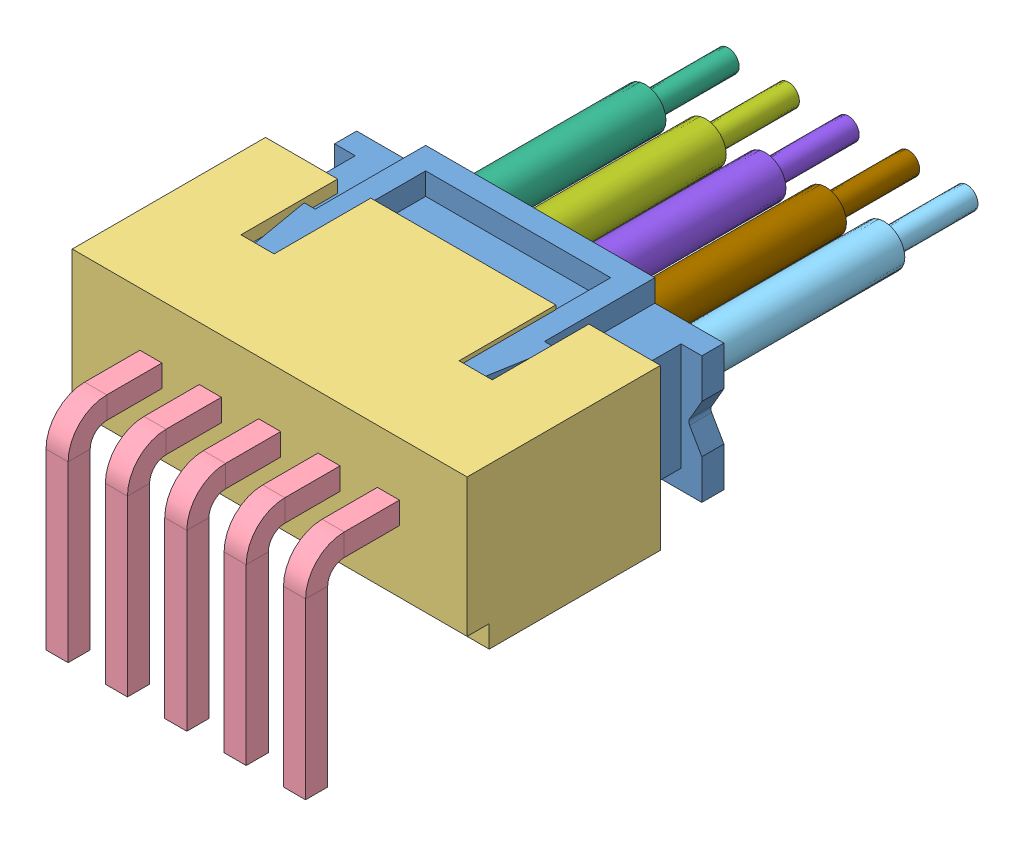
SolidWorks assembly Assem2, configuration Default. Lengths in mm.
Overall size (14.3 9.85 24.36).
17 component instances, 9 part files, 33 mates.
Components (placement in the parent):
- JST - XH MALE 5 pin-1: JST - XH MALE 5 pin [Default] at (8.2428 8.3107 7.5483) size (13.3 5.4 8.4)
- Part1-2: Part1 [Default] at (12.5428 8.6607 13.8683) x (1 0 0) z (0 1 0) size (1.8 6 3.23)
- Part1-3: Part1 [Default] at (10.3928 8.6607 13.8683) x (1 0 0) z (0 1 0) size (1.8 6 3.23)
- Part1-4: Part1 [Default] at (6.0928 8.6607 13.8683) x (1 0 0) z (0 1 0) size (1.8 6 3.23)
- Part1-5: Part1 [Default] at (8.2428 8.6607 13.8683) x (1 0 0) z (0 1 0) size (1.8 6 3.23)
- Part1-6: Part1 [Default] at (3.9428 8.6607 13.8683) x (1 0 0) z (0 1 0) size (1.8 6 3.23)
- Part 2-1: Part 2 [Default] at (8.2428 8.5107 9.5483) x (-1 0 0) z (0 1 0) size (14.3 7 5.8)
- Part3-1: Part3 [Default] at (10.3928 9.0607 19.5483) x (0 0 1) z (-1 0 0) size (9.7 7.9 0.8)
- Part3-2: Part3 [Default] at (12.5428 9.0607 19.5483) x (0 0 1) z (-1 0 0) size (9.7 7.9 0.8)
- Part3-3: Part3 [Default] at (8.2428 9.0607 19.5483) x (0 0 1) z (-1 0 0) size (9.7 7.9 0.8)
- Part3-4: Part3 [Default] at (3.9428 9.0607 19.5483) x (0 0 1) z (-1 0 0) size (9.7 7.9 0.8)
- Part3-6: Part3 [Default] at (6.0928 9.0607 19.5483) x (0 0 1) z (-1 0 0) size (9.7 7.9 0.8)
- Part4-1: Part4 [Default] at (12.5672 8.3011 -1.3782) size (1.5 1.5 16)
- Part5-1: Part5 [Default] at (3.9383 8.295 -1.3574) size (1.5 1.5 16)
- Part6-1: Part6 [Default] at (6.0987 8.2852 -1.381) size (1.5 1.5 16)
- Part7-1: Part7 [Default] at (8.2574 8.3033 -1.386) size (1.5 1.5 16)
- Part8-1: Part8 [Default] at (10.4186 8.2877 -1.4154) size (1.5 1.5 16)
Mates (geometry in assembly coordinates):
- Width1: width anti-aligned: plane of Part1-2 through (11.6428 7.5107 11.7683) normal (-1 0 0); plane of Part1-2 through (13.4428 7.5107 11.7683) normal (1 0 0); plane of JST - XH MALE 5 pin-1 through (11.5428 10.0607 14.2483) normal (1 0 0); plane of JST - XH MALE 5 pin-1 through (13.5428 10.0607 14.2483) normal (-1 0 0)
- Width2: width anti-aligned: plane of Part1-2 through (11.6428 9.8107 11.7683) normal (0 1 0); plane of Part1-2 through (11.6428 7.5107 11.7683) normal (0 -1 0); plane of JST - XH MALE 5 pin-1 through (11.5428 10.0607 14.2483) normal (0 -1 0); plane of JST - XH MALE 5 pin-1 through (11.5428 7.2607 14.2483) normal (0 1 0)
- Width3: width anti-aligned: plane of Part1-3 through (9.4928 9.8107 11.7683) normal (0 1 0); plane of Part1-3 through (9.4928 7.5107 11.7683) normal (0 -1 0); plane of JST - XH MALE 5 pin-1 through (9.3928 10.0607 14.2483) normal (0 -1 0); plane of JST - XH MALE 5 pin-1 through (10.7928 7.2607 14.2483) normal (0 1 0)
- Width4: width anti-aligned: plane of Part1-3 through (9.4928 7.5107 11.7683) normal (-1 0 0); plane of Part1-3 through (11.2928 7.5107 11.7683) normal (1 0 0); plane of JST - XH MALE 5 pin-1 through (9.3928 10.0607 14.2483) normal (1 0 0); plane of JST - XH MALE 5 pin-1 through (11.3928 10.0607 14.2483) normal (-1 0 0)
- Width5: width anti-aligned: plane of Part1-5 through (7.3428 9.8107 11.7683) normal (0 1 0); plane of Part1-5 through (7.3428 7.5107 11.7683) normal (0 -1 0); plane of JST - XH MALE 5 pin-1 through (7.2428 10.0607 14.2483) normal (0 -1 0); plane of JST - XH MALE 5 pin-1 through (7.2428 7.2607 14.2483) normal (0 1 0)
- Width6: width anti-aligned: plane of Part1-5 through (7.3428 7.5107 11.7683) normal (-1 0 0); plane of Part1-5 through (9.1428 7.5107 11.7683) normal (1 0 0); plane of JST - XH MALE 5 pin-1 through (7.2428 10.0607 14.2483) normal (1 0 0); plane of JST - XH MALE 5 pin-1 through (9.2428 10.0607 14.2483) normal (-1 0 0)
- Width7: width anti-aligned: plane of Part1-4 through (5.1928 9.8107 11.7683) normal (0 1 0); plane of Part1-4 through (5.1928 7.5107 11.7683) normal (0 -1 0); plane of JST - XH MALE 5 pin-1 through (5.0928 10.0607 14.2483) normal (0 -1 0); plane of JST - XH MALE 5 pin-1 through (6.4928 7.2607 14.2483) normal (0 1 0)
- Width8: width anti-aligned: plane of Part1-4 through (5.1928 7.5107 11.7683) normal (-1 0 0); plane of Part1-4 through (6.9928 7.5107 11.7683) normal (1 0 0); plane of JST - XH MALE 5 pin-1 through (5.0928 10.0607 14.2483) normal (1 0 0); plane of JST - XH MALE 5 pin-1 through (7.0928 10.0607 14.2483) normal (-1 0 0)
- Width9: width anti-aligned: plane of Part1-6 through (3.0428 7.5107 11.7683) normal (-1 0 0); plane of Part1-6 through (4.8428 7.5107 11.7683) normal (1 0 0); plane of JST - XH MALE 5 pin-1 through (2.9428 10.0607 14.2483) normal (1 0 0); plane of JST - XH MALE 5 pin-1 through (4.9428 10.0607 14.2483) normal (-1 0 0)
- Width10: width anti-aligned: plane of Part1-6 through (3.0428 9.8107 11.7683) normal (0 1 0); plane of Part1-6 through (3.0428 7.5107 11.7683) normal (0 -1 0); plane of JST - XH MALE 5 pin-1 through (2.9428 10.0607 14.2483) normal (0 -1 0); plane of JST - XH MALE 5 pin-1 through (4.3428 7.2607 14.2483) normal (0 1 0)
- Distance1: distance = 0.38 mm anti-aligned: plane of Part1-2 through (12.5428 8.6607 13.8683) normal (0 0 1); plane of JST - XH MALE 5 pin-1 through (8.2428 8.3107 14.2483) normal (0 0 -1)
- Distance2: distance = 0.38 mm anti-aligned: plane of Part1-3 through (10.3928 8.6607 13.8683) normal (0 0 1); plane of JST - XH MALE 5 pin-1 through (8.2428 8.3107 14.2483) normal (0 0 -1)
- Distance3: distance = 0.38 mm anti-aligned: plane of Part1-5 through (8.2428 8.6607 13.8683) normal (0 0 1); plane of JST - XH MALE 5 pin-1 through (8.2428 8.3107 14.2483) normal (0 0 -1)
- Distance4: distance = 0.38 mm anti-aligned: plane of Part1-6 through (3.9428 8.6607 13.8683) normal (0 0 1); plane of JST - XH MALE 5 pin-1 through (8.2428 8.3107 14.2483) normal (0 0 -1)
- Distance5: distance = 0.38 mm anti-aligned: plane of Part1-4 through (6.0928 8.6607 13.8683) normal (0 0 1); plane of JST - XH MALE 5 pin-1 through (8.2428 8.3107 14.2483) normal (0 0 -1)
- Width11: width anti-aligned: plane of JST - XH MALE 5 pin-1 through (2.3428 6.1607 14.5483) normal (-1 0 0); plane of JST - XH MALE 5 pin-1 through (14.1428 6.1607 14.5483) normal (1 0 0); plane of Part 2-1 through (2.2428 6.0607 14.5483) normal (1 0 0); plane of Part 2-1 through (14.2428 6.0607 14.5483) normal (-1 0 0)
- Width12: width anti-aligned: plane of JST - XH MALE 5 pin-1 through (2.3428 10.4607 14.5483) normal (0 1 0); plane of JST - XH MALE 5 pin-1 through (8.2428 6.5607 7.5483) normal (0 -1 0); plane of Part 2-1 through (14.2428 10.9607 14.5483) normal (0 -1 0); plane of Part 2-1 through (14.2428 6.0607 14.5483) normal (0 1 0)
- LimitDistance1: limit distance = 0 mm anti-aligned: plane of Part 2-1 through (8.2428 8.5107 14.5483) normal (0 0 -1); plane of JST - XH MALE 5 pin-1 through (8.2428 8.3107 14.5483) normal (0 0 1)
- Coincident1: coincident aligned: plane of Part3-4 through (4.3428 8.0607 19.9483) normal (0 0 1); plane of Part3-6 through (6.4928 8.0607 19.9483) normal (0 0 1)
- Coincident2: coincident aligned: plane of Part3-1 through (10.7928 8.0607 19.9483) normal (0 0 1); plane of Part3-6 through (6.4928 8.0607 19.9483) normal (0 0 1)
- Coincident3: coincident aligned: plane of Part3-1 through (10.7928 8.0607 19.9483) normal (0 0 1); plane of Part3-3 through (8.6428 8.0607 19.9483) normal (0 0 1)
- Coincident4: coincident aligned: plane of Part3-2 through (12.9428 8.0607 19.9483) normal (0 0 1); plane of Part3-3 through (8.6428 8.0607 19.9483) normal (0 0 1)
- Coincident5: coincident aligned: plane of Part3-4 through (4.3428 9.4607 18.5483) normal (0 1 0); plane of Part3-6 through (6.4928 9.4607 18.5483) normal (0 1 0)
- Coincident6: coincident aligned: plane of Part3-1 through (10.7928 9.4607 18.5483) normal (0 1 0); plane of Part3-6 through (6.4928 9.4607 18.5483) normal (0 1 0)
- Coincident7: coincident aligned: plane of Part3-1 through (10.7928 9.4607 18.5483) normal (0 1 0); plane of Part3-3 through (8.6428 9.4607 18.5483) normal (0 1 0)
- Coincident8: coincident aligned: plane of Part3-2 through (12.9428 9.4607 18.5483) normal (0 1 0); plane of Part3-3 through (8.6428 9.4607 18.5483) normal (0 1 0)
- Coincident9: coincident anti-aligned: plane of Part 2-1 through (3.5428 9.4607 6.5483) normal (0 -1 0); plane of Part3-4 through (4.3428 9.4607 18.5483) normal (0 1 0)
- Coincident10: coincident anti-aligned: plane of Part 2-1 through (4.3428 9.4607 6.5483) normal (-1 0 0); plane of Part3-4 through (4.3428 9.4607 18.5483) normal (1 0 0)
- Coincident11: coincident anti-aligned: plane of Part 2-1 through (6.4928 9.4607 6.5483) normal (-1 0 0); plane of Part3-6 through (6.4928 9.4607 18.5483) normal (1 0 0)
- Coincident12: coincident anti-aligned: plane of Part 2-1 through (8.6428 9.4607 6.5483) normal (-1 0 0); plane of Part3-3 through (8.6428 9.4607 18.5483) normal (1 0 0)
- Coincident13: coincident anti-aligned: plane of Part 2-1 through (10.7928 9.4607 6.5483) normal (-1 0 0); plane of Part3-1 through (10.7928 9.4607 18.5483) normal (1 0 0)
- Coincident14: coincident anti-aligned: plane of Part 2-1 through (12.1428 9.4607 6.5483) normal (1 0 0); plane of Part3-2 through (12.1428 9.4607 18.5483) normal (-1 0 0)
- Distance7: distance = 0.7 mm aligned: plane of Part3-6 through (6.0928 9.0607 10.2483) normal (0 0 -1); plane of Part 2-1 through (8.2428 8.5107 9.5483) normal (0 0 -1)
